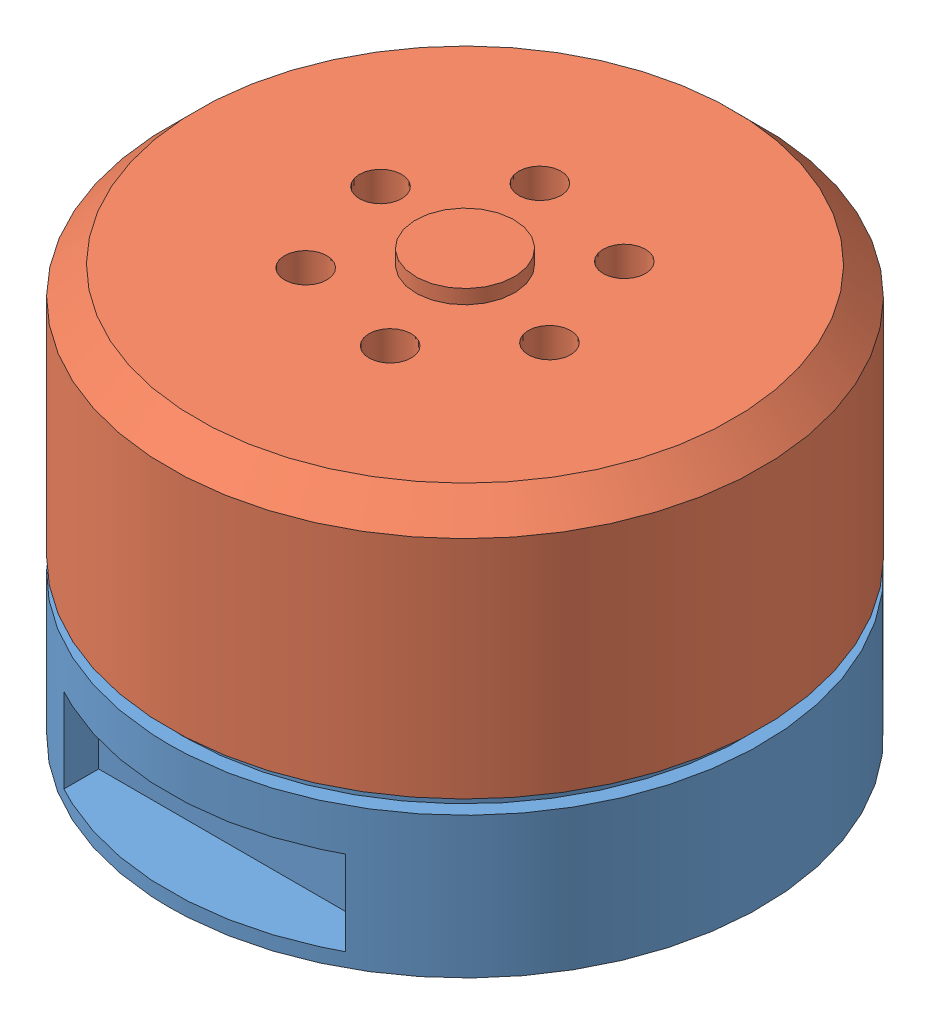
SolidWorks assembly 3510, configuration 默认. Lengths in mm.
Overall size (52.44 31.5 52.44).
2 component instances, 2 part files, 2 mates.
Components (placement in the parent):
- 3510定子-1: 3510定子 [默认] at origin size (42 27.5 42)
- 3510转子-1: 3510转子 [默认] at (0 29 0) x (-0.956343 0 0.292248) z (0.292248 0 0.956343) size (42 19 42)
Mates (geometry in assembly coordinates):
- 同心1: concentric anti-aligned: circle of 3510定子-1; circle of 3510转子-1
- 重合2: coincident anti-aligned: plane of 3510定子-1 through (0 26 0) normal (0 1 0); plane of 3510转子-1 through (0 26 0) normal (0 -1 0)
